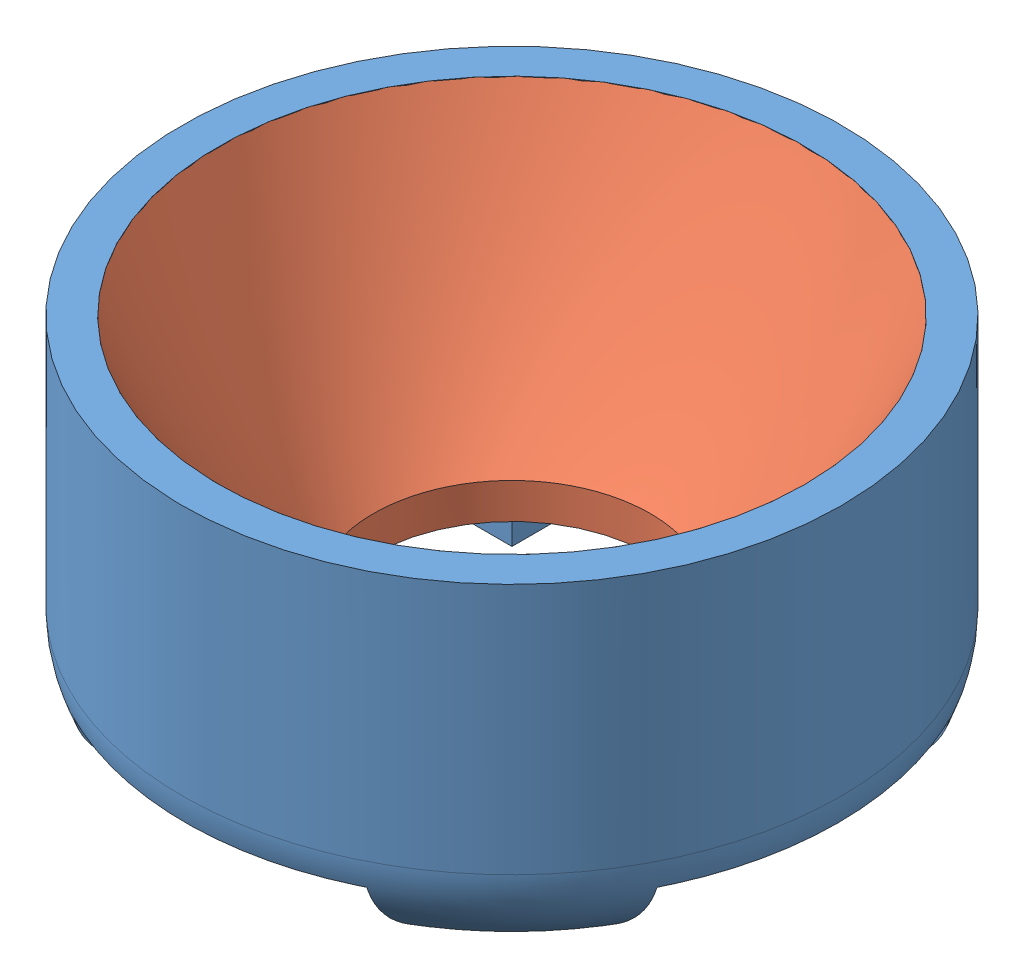
SolidWorks assembly Reflector, configuration Default. Lengths in mm.
Overall size (14.29 7.51 14.29).
2 component instances, 2 part files, 2 mates.
Components (placement in the parent):
- Reflector Shell-1: Reflector Shell [Default] at (4.22 3.162 10.2204) size (14.29 12.7 14.29)
- Reflector Core-1: Reflector Core [Default] at (4.22 3.162 10.2204) size (12.7 6.72 12.7)
Mates (geometry in assembly coordinates):
- Concentric2: concentric aligned: cylinder of Reflector Shell-1 through (4.22 -244.1233 10.2204) axis (0 -1 0) radius 6.35; cylinder of Reflector Core-1 through (4.22 -844.8957 10.2204) axis (0 -1 0) radius 6.35
- Coincident1: coincident anti-aligned: plane of Reflector Shell-1 through (9.3 3.162 10.2204) normal (0 1 0); plane of Reflector Core-1 through (10.57 3.162 10.2204) normal (0 -1 0)
